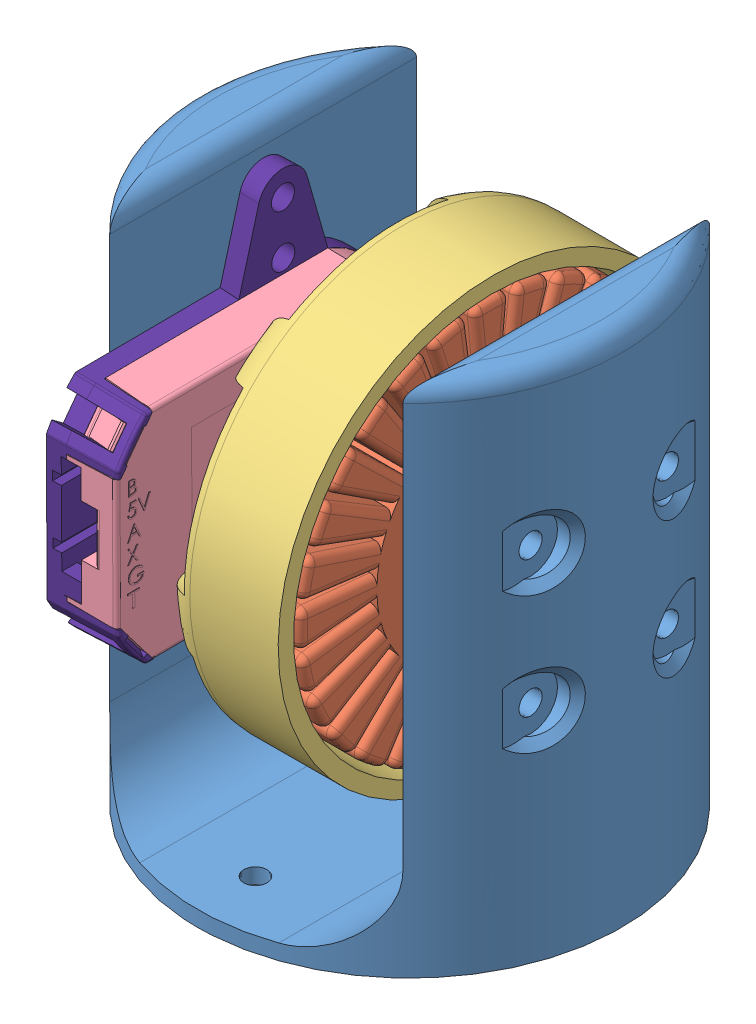
SolidWorks assembly TestStandAssem, configuration Default. Lengths in mm.
Overall size (55 88.5 88.5).
19 component instances, 17 part files, 6 mates.
Components (placement in the parent):
- TestStand-1: TestStand [Default] at (-1.0096 17.7378 57.075) size (55 67 55)
- MN5008-1: MN5008 [Default] at (45.0143 18.0079 17.5675) x (0 0.707107 -0.707107) z (0 0.707107 0.707107) size (73.2 32 73.2)
  - Stator-1: Stator [Default] at (-1.9641 27.0239 53.908) size (49.92 18.31 49.92)
  - Rotor-1: Rotor [Default] at (-1.9641 27.0239 53.908) x (-0.916557 0 -0.399905) z (0 -1 0) size (55.6 55.6 23.75)
- amt102-v-1: amt102-v [Default] at (-16.3896 54.7378 57.075) x (0 -0.99998 -0.006277) z (1 0 0) size (52.34 43.39 9.15)
  - amt102-v_02-1: amt102-v_02 [Default] at origin size (28.6 43.26 6.55)
  - amt102-v_04-1: amt102-v_04 [Default] at origin size (14 14 5.67)
  - amt102-v_05-1: amt102-v_05 [Default] at origin size (17.3 17.3 3.2)
  - amt102-v_06-1: amt102-v_06 [Default] at origin size (11.8 11.8 7.81)
  - amt102-v_07-1: amt102-v_07 [Default] at origin size (26.5 26.62 0.41)
  - amt102-v_08-1: amt102-v_08 [Default] at origin size (26 26 0.3)
  - amt102-v_09-1: amt102-v_09 [Default] at origin size (26.63 29.52 0.81)
  - amt102-v_10-1: amt102-v_10 [Default] at origin size (3.37 3.37 1)
  - amt102-v_11-1: amt102-v_11 [Default] at origin size (2.47 10.89 4.41)
  - amt102-v_12-1: amt102-v_12 [Default] at origin size (2.47 10.89 4.41)
  - amt102-v_13-1: amt102-v_13 [Default] at origin size (2.47 10.89 4.41)
  - amt102-v_14-1: amt102-v_14 [Default] at origin size (2.47 10.89 4.41)
  - amt102-v_15-1: amt102-v_15 [Default] at origin size (2.47 10.89 4.41)
  - AMT-B0-W-1: AMT-B0-W [Default] at (0 0 0.15) size (52.34 43.39 9.15)
Mates (geometry in assembly coordinates):
- Concentric1: concentric aligned: cylinder of TestStand-1 through (26.4904 63.5766 48.2362) axis (-1 0 0) radius 1.5; cylinder of MN5008-1/Stator-1 through (17.9904 63.5766 48.2362) axis (-1 0 0) radius 1.5
- Concentric3: concentric aligned: cylinder of TestStand-1 through (26.4904 63.5766 65.9138) axis (-1 0 0) radius 1.5; cylinder of MN5008-1/Stator-1 through (17.9904 63.5766 65.9138) axis (-1 0 0) radius 1.5
- Coincident1: coincident anti-aligned: plane of TestStand-1 through (17.9904 84.7378 37.1941) normal (-1 0 0); plane of MN5008-1/Stator-1 through (17.9904 54.7378 57.075) normal (1 0 0)
- Coincident2: coincident anti-aligned: plane of TestStand-1 through (-20.0096 84.7378 37.1941) normal (1 0 0); plane of amt102-v-1/AMT-B0-W-1 through (-20.0096 31.8084 56.7173) normal (-1 0 0)
- Concentric5: concentric anti-aligned: cylinder of MN5008-1/Rotor-1 through (-70.9996 54.7378 57.075) axis (-1 0 0) radius 2; cone of amt102-v-1/amt102-v_06-1 through (-16.2648 54.7378 57.075) axis (1 0 0)
- Parallel2: parallel aligned: cylinder of TestStand-1 through (-28.5096 77.6678 57.075) axis (1 0 0) radius 1.5; cone of amt102-v-1/AMT-B0-W-1 through (-17.5096 77.6699 57.0027) axis (1 0 0)
